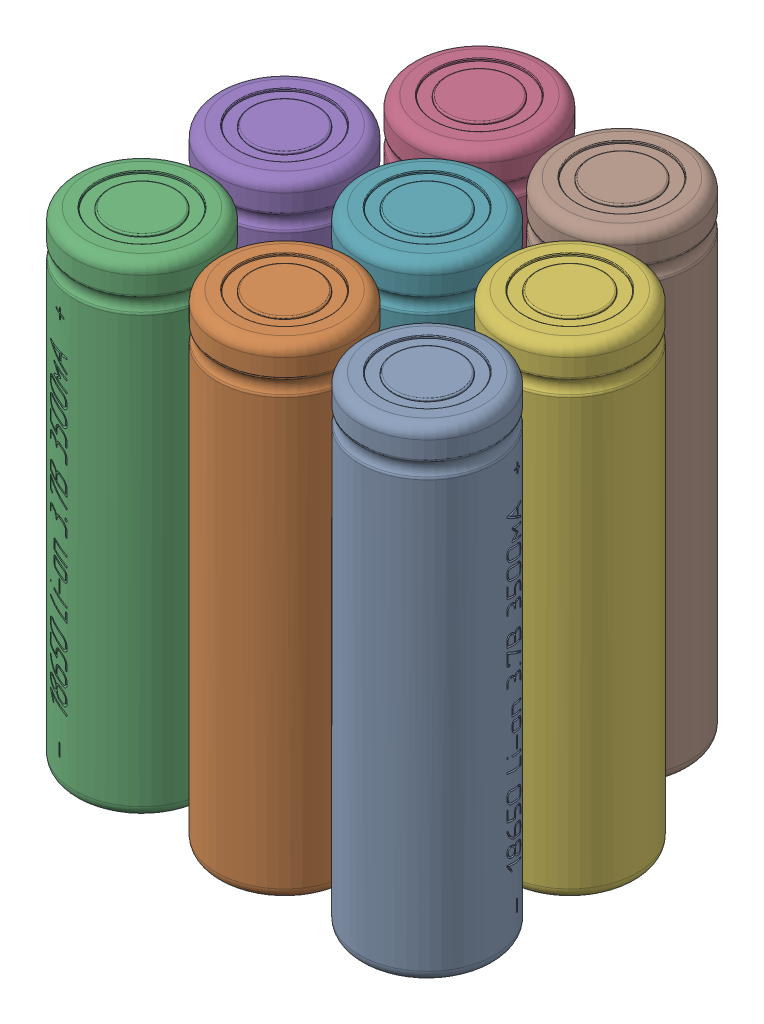
SolidWorks assembly battery_pack, configuration Default. Lengths in mm.
Overall size (61.85 65 42.63).
8 component instances, 1 part files, 16 mates.
Components (placement in the parent):
- 18650-9: 18650 [По умолчанию] x (0 1 0) z (0.875717 0 -0.482826) size (65 18.2 18.21)
- 18650-10: 18650 [По умолчанию] at (-19.2128 0 0) x (0 1 0) z (0.168066 0 -0.985776) size (65 18.2 18.21)
- 18650-11: 18650 [По умолчанию] at (-38.4256 0 0) x (0 1 0) z (-0.194298 0 0.980943) size (65 18.2 18.21)
- 18650-12: 18650 [По умолчанию] at (-28.8192 0 -35.8516) x (0 1 0) z (-0.006073 0 0.999982) size (65 18.2 18.21) (hidden)
- 18650-13: 18650 [По умолчанию] at (-38.4256 0 -19.2128) x (0 1 0) z (0.969487 0 -0.245141) size (65 18.2 18.21)
- 18650-14: 18650 [По умолчанию] at (0 0 -19.2128) x (0 1 0) z (-0.065022 0 0.997884) size (65 18.2 18.21)
- 18650-15: 18650 [По умолчанию] at (-19.2128 0 -19.2128) x (0 1 0) z (-0.082198 0 0.996616) size (65 18.2 18.21)
- 18650-16: 18650 [По умолчанию] at (-9.6064 0 -35.8516) x (0 1 0) z (-0.088185 0 0.996104) size (65 18.2 18.21) (hidden)
Mates (geometry in assembly coordinates):
- Coincident20: coincident: point of 18650-9; point of assembly
- Coincident21: coincident anti-aligned: plane of 18650-9 through (0 0 0) normal (0 -1 0)
- Coincident22: coincident: point of 18650-10; point of assembly
- Coincident23: coincident anti-aligned: plane of 18650-10 through (-19.2128 0 0) normal (0 -1 0)
- Coincident24: coincident: point of 18650-13; point of assembly
- Coincident25: coincident anti-aligned: plane of 18650-13 through (-38.4256 0 -19.2128) normal (0 -1 0)
- Coincident26: coincident: point of 18650-11; point of assembly
- Coincident27: coincident anti-aligned: plane of 18650-11 through (-38.4256 0 0) normal (0 -1 0)
- Coincident28: coincident: point of 18650-12; point of assembly
- Coincident29: coincident anti-aligned: plane of 18650-12 through (-28.8192 0 -35.8516) normal (0 -1 0)
- Coincident30: coincident: point of 18650-14; point of assembly
- Coincident31: coincident anti-aligned: plane of 18650-14 through (0 0 -19.2128) normal (0 -1 0)
- Coincident32: coincident: point of 18650-16; point of assembly
- Coincident33: coincident anti-aligned: plane of 18650-16 through (-9.6064 0 -35.8516) normal (0 -1 0)
- Coincident34: coincident: point of 18650-15; point of assembly
- Coincident35: coincident anti-aligned: plane of 18650-15 through (-19.2128 0 -19.2128) normal (0 -1 0)
